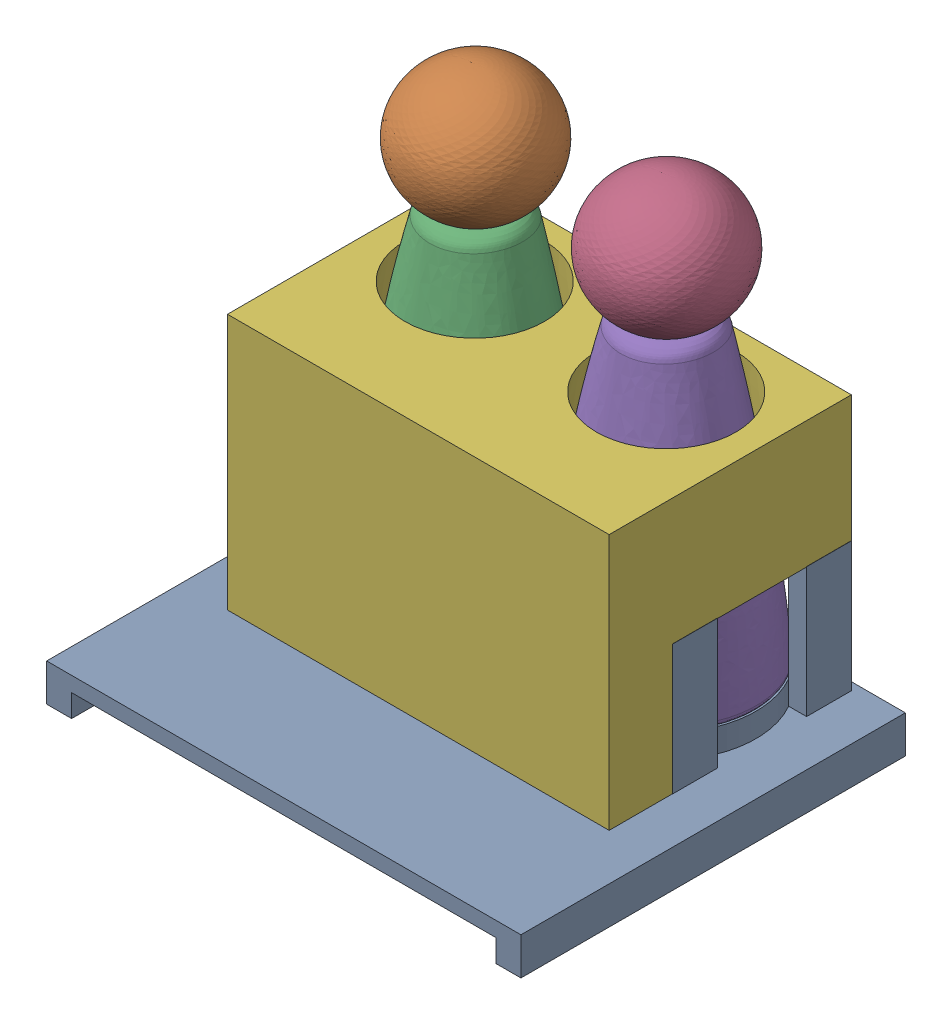
SolidWorks assembly Pilot crew, configuration Default. Lengths in mm.
Overall size (95 96.4 77).
4 component instances, 3 part files, 8 mates.
Components (placement in the parent):
- crew platform(permanant)-2: crew platform(permanant) [Default] at origin size (95 33.5 77)
- crew-passenger-1: crew-passenger [Default] at (-19.1333 3 -19.0489) x (0.999737 0 0.022915) z (-0.022915 0 0.999737) size (36.14 88.9 36.75)
- crew-passenger-2: crew-passenger [Default] at (19.1333 3 -19.0489) size (36.14 88.9 36.75)
- crew seatbelt-1: crew seatbelt [Default] at (0 3 -1.1419) size (76.45 51.31 48.51)
Mates (geometry in assembly coordinates):
- Coincident3: coordinate: point of crew platform(permanant)-2
- Coincident4: coincident: point of crew-passenger-1; plane of crew-passenger-2 through (19.1333 3 -19.0489) normal (0 -1 0)
- Concentric1: concentric aligned: cylinder of crew platform(permanant)-2 through (-19.1333 7.7625 -19.0489) axis (0 -1 0) radius 13.97; cylinder of crew-passenger-1 through (-19.1333 7.445 -19.0489) axis (0 -1 0) radius 13.97
- Concentric2: concentric aligned: cylinder of crew platform(permanant)-2 through (19.1333 7.7625 -19.0489) axis (0 -1 0) radius 13.97; cylinder of crew-passenger-2 through (19.1333 7.445 -19.0489) axis (0 -1 0) radius 13.97
- Coincident5: coincident anti-aligned: plane of crew platform(permanant)-2 through (0 3 0) normal (0 1 0); plane of crew-passenger-1 through (-19.1333 3 -19.0489) normal (0 -1 0)
- Coincident6: coincident anti-aligned: plane of crew platform(permanant)-2 through (0 29 -1.1419) normal (0 0 1); plane of crew seatbelt-1 through (-38.227 54.308 -1.1419) normal (0 0 -1)
- Width1: width anti-aligned: plane of crew seatbelt-1 through (38.227 54.308 11.5581) normal (1 0 0); plane of crew platform(permanant)-2 through (-38.227 54.308 -1.1419) normal (-1 0 0); plane of crew seatbelt-1 through (-38.2667 29 0) normal (-1 0 0); plane of crew platform(permanant)-2 through (38.2667 29 0) normal (1 0 0)
- Coincident7: coincident anti-aligned: plane of crew platform(permanant)-2 through (0 3 0) normal (0 1 0); plane of crew seatbelt-1 through (0 3 -1.1419) normal (0 -1 0)
